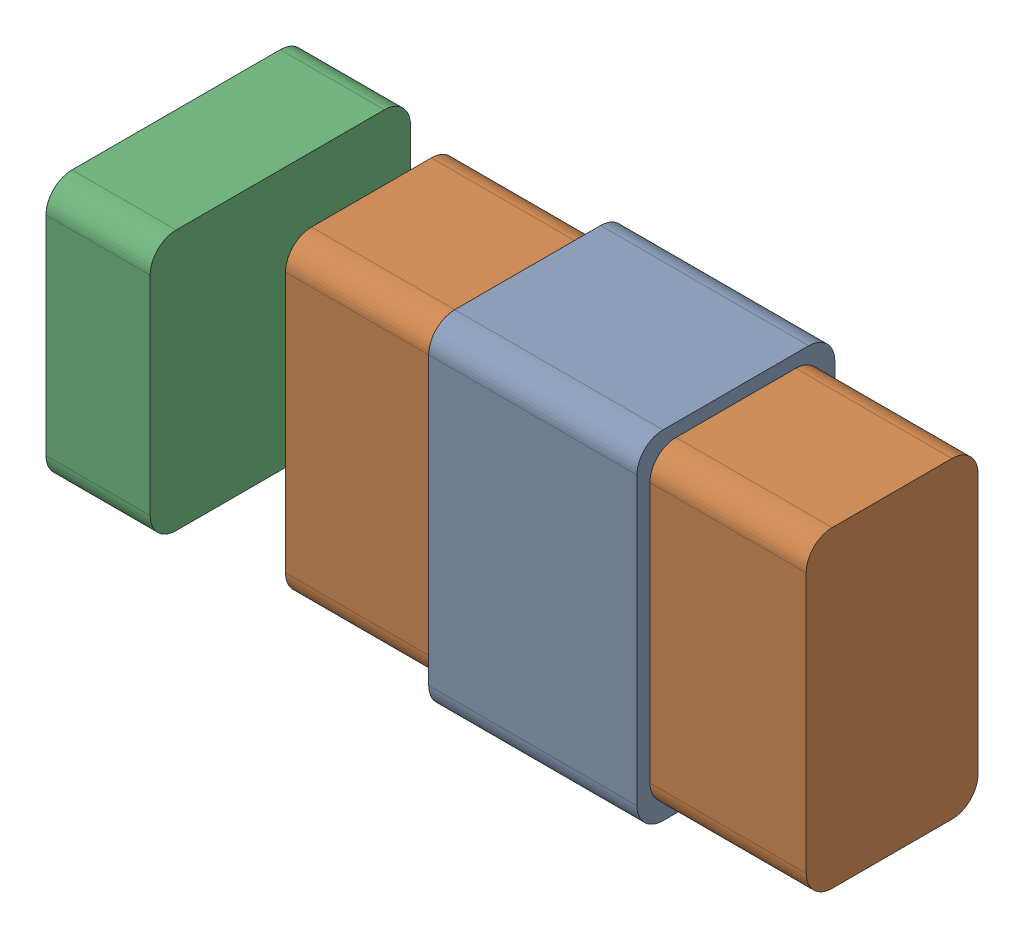
SolidWorks assembly COMSOL_Assembly, configuration Default. Lengths in mm.
Overall size (1.38 0.65 0.5).
3 component instances, 3 part files, 7 mates.
Components (placement in the parent):
- COMSOL_Coil-1: COMSOL_Coil [Default] at (-0.2624 -0.0651 0.1827) size (0.4 0.65 0.38)
- COMSOL_Core-1: COMSOL_Core [Default] at (-0.5624 -0.0401 0.2077) size (1 0.6 0.33)
- COMSOL_Magnet-1: COMSOL_Magnet [Default] at (-0.7374 0.0099 0.6227) x (0 0 -1) z (0 1 0) size (0.5 0.2 0.5)
Mates (geometry in assembly coordinates):
- Coincident1: coincident anti-aligned: plane of COMSOL_Coil-1 through (-0.2624 0.5599 0.2077) normal (0 0 1); plane of COMSOL_Core-1 through (-0.5624 0.5599 0.2077) normal (0 0 -1)
- Coincident2: coincident anti-aligned: plane of COMSOL_Coil-1 through (-0.2624 0.5599 0.5377) normal (0 -1 0); plane of COMSOL_Core-1 through (-0.5624 0.5599 0.2077) normal (0 1 0)
- Coincident6: coincident aligned: line of COMSOL_Coil-1 through (-0.0624 0.0099 0.2077) axis (0 1 0); line of COMSOL_Core-1 through (-0.0624 0.0099 0.2077) axis (0 1 0)
- Parallel3: parallel: plane of COMSOL_Core-1 through (-0.5624 0.5599 0.2077) normal (-1 0 0); plane of COMSOL_Magnet-1 through (-0.7938 0.0099 0.6227) normal (1 0 0)
- Concentric1: concentric: circle of COMSOL_Core-1; circle of COMSOL_Magnet-1
- Parallel4: parallel: line of COMSOL_Core-1 through (-0.5624 0.5099 0.2077) axis (0 -1 0); line of COMSOL_Magnet-1 through (-0.7938 0.4599 0.1227) axis (0 -1 0)
- Distance1: distance = 0.175 mm anti-aligned: plane of COMSOL_Magnet-1 through (-0.7374 0.0099 0.6227) normal (1 0 0); plane of COMSOL_Core-1 through (-0.5624 0.5599 0.2077) normal (-1 0 0)
